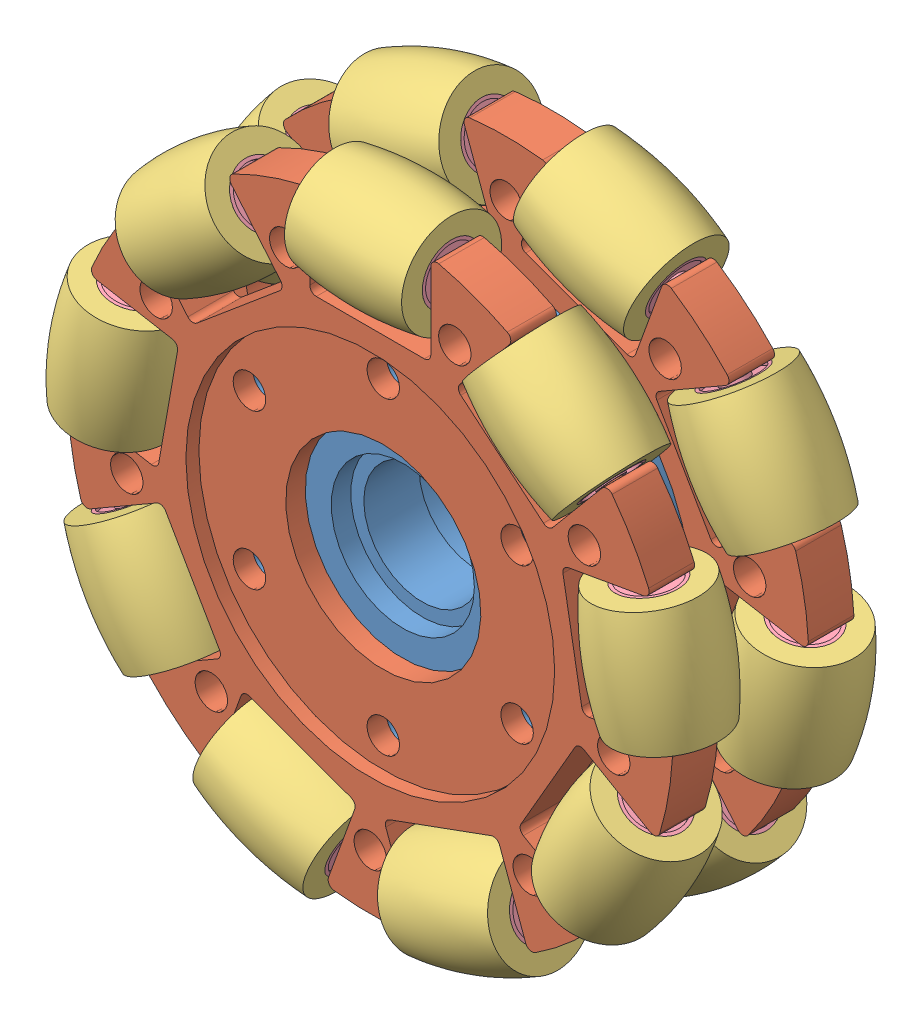
SolidWorks assembly 100mm Omni Wheel, configuration Default. Lengths in mm.
Overall size (131.92 131.45 55.1).
60 component instances, 5 part files, 8 mates.
Components (placement in the parent):
- Core-1: Core [Default] at origin size (56 56 18)
- Single Side-2: Single Side [Default] at (0 0 10.5) x (-0.5 0.866025 0) z (0 0 1) size (107.72 106.08 23.21)
  - Frame-1: Frame [Default] at origin size (92.88 91.83 7)
  - Roller_New-1: Roller_New [預設] at (0 41.5 0) x (1 0 0) z (0 -0.498092 0.867124) size (18 17 17)
  - MR93zz_3x9x4mm-1: MR93zz_3x9x4mm [預設] at (7 41.5 0) x (0 0 -1) z (1 0 0) size (9 9 4)
  - MR93zz_3x9x4mm-2: MR93zz_3x9x4mm [預設] at (-7 41.5 0) x (0 0 1) z (-1 0 0) size (9 9 4)
  - Roller_New-2: Roller_New [預設] at (-26.6757 31.7908 0) x (0.766044 0.642788 0) z (0.320168 -0.381561 0.867124) size (18 17 17)
  - Roller_New-3: Roller_New [預設] at (-40.8695 7.2064 0) x (0.173648 0.984808 0) z (0.490525 -0.086493 0.867124) size (18 17 17)
  - Roller_New-4: Roller_New [預設] at (-35.9401 -20.75 0) x (-0.5 0.866025 0) z (0.431361 0.249046 0.867124) size (18 17 17)
  - Roller_New-5: Roller_New [預設] at (-14.1938 -38.9972 0) x (-0.939693 0.34202 0) z (0.170358 0.468054 0.867124) size (18 17 17)
  - Roller_New-6: Roller_New [預設] at (14.1938 -38.9972 0) x (-0.939693 -0.34202 0) z (-0.170358 0.468054 0.867124) size (18 17 17)
  - Roller_New-7: Roller_New [預設] at (35.9401 -20.75 0) x (-0.5 -0.866025 0) z (-0.431361 0.249046 0.867124) size (18 17 17)
  - Roller_New-8: Roller_New [預設] at (40.8695 7.2064 0) x (0.173648 -0.984808 0) z (-0.490525 -0.086493 0.867124) size (18 17 17)
  - Roller_New-9: Roller_New [預設] at (26.6757 31.7908 0) x (0.766044 -0.642788 0) z (-0.320168 -0.381561 0.867124) size (18 17 17)
  - MR93zz_3x9x4mm-3: MR93zz_3x9x4mm [預設] at (-32.038 27.2913 0) x (0 0 1) z (-0.766044 -0.642788 0) size (9 9 4)
  - MR93zz_3x9x4mm-4: MR93zz_3x9x4mm [預設] at (-42.0851 0.3127 0) x (0 0 1) z (-0.173648 -0.984808 0) size (9 9 4)
  - MR93zz_3x9x4mm-5: MR93zz_3x9x4mm [預設] at (-32.4401 -26.8122 0) x (0 0 1) z (0.5 -0.866025 0) size (9 9 4)
  - MR93zz_3x9x4mm-6: MR93zz_3x9x4mm [預設] at (-7.616 -41.3914 0) x (0 0 1) z (0.939693 -0.34202 0) size (9 9 4)
  - MR93zz_3x9x4mm-7: MR93zz_3x9x4mm [預設] at (20.7717 -36.6031 0) x (0 0 1) z (0.939693 0.34202 0) size (9 9 4)
  - MR93zz_3x9x4mm-8: MR93zz_3x9x4mm [預設] at (39.4401 -14.6878 0) x (0 0 1) z (0.5 0.866025 0) size (9 9 4)
  - MR93zz_3x9x4mm-9: MR93zz_3x9x4mm [預設] at (39.654 14.1001 0) x (0 0 1) z (-0.173648 0.984808 0) size (9 9 4)
  - MR93zz_3x9x4mm-10: MR93zz_3x9x4mm [預設] at (21.3134 36.2904 0) x (0 0 1) z (-0.766044 0.642788 0) size (9 9 4)
  - MR93zz_3x9x4mm-11: MR93zz_3x9x4mm [預設] at (-21.3134 36.2904 0) x (0 0 -1) z (0.766044 0.642788 0) size (9 9 4)
  - MR93zz_3x9x4mm-12: MR93zz_3x9x4mm [預設] at (-39.654 14.1001 0) x (0 0 -1) z (0.173648 0.984808 0) size (9 9 4)
  - MR93zz_3x9x4mm-13: MR93zz_3x9x4mm [預設] at (-39.4401 -14.6878 0) x (0 0 -1) z (-0.5 0.866025 0) size (9 9 4)
  - MR93zz_3x9x4mm-14: MR93zz_3x9x4mm [預設] at (-20.7717 -36.6031 0) x (0 0 -1) z (-0.939693 0.34202 0) size (9 9 4)
  - MR93zz_3x9x4mm-15: MR93zz_3x9x4mm [預設] at (7.616 -41.3914 0) x (0 0 -1) z (-0.939693 -0.34202 0) size (9 9 4)
  - MR93zz_3x9x4mm-16: MR93zz_3x9x4mm [預設] at (32.4401 -26.8122 0) x (0 0 -1) z (-0.5 -0.866025 0) size (9 9 4)
  - MR93zz_3x9x4mm-17: MR93zz_3x9x4mm [預設] at (42.0851 0.3127 0) x (0 0 -1) z (0.173648 -0.984808 0) size (9 9 4)
  - MR93zz_3x9x4mm-18: MR93zz_3x9x4mm [預設] at (32.038 27.2913 0) x (0 0 -1) z (0.766044 -0.642788 0) size (9 9 4)
- 8mm Hub-1: 8mm Hub [預設] at (-0.1077 -0.0622 -12) x (0.5 -0.866025 0) z (0 0 -1) size (56.7 56.7 26)
- Single Side-3: Single Side [Default] at (-0.1077 -0.0622 -10.5) x (0.5 -0.866025 0) z (0 0 1) size (107.72 106.08 23.21)
  - Frame-1: Frame [Default] at origin size (92.88 91.83 7)
  - Roller_New-1: Roller_New [預設] at (0 41.5 0) x (1 0 0) z (0 -0.498092 0.867124) size (18 17 17)
  - MR93zz_3x9x4mm-1: MR93zz_3x9x4mm [預設] at (7 41.5 0) x (0 0 -1) z (1 0 0) size (9 9 4)
  - MR93zz_3x9x4mm-2: MR93zz_3x9x4mm [預設] at (-7 41.5 0) x (0 0 1) z (-1 0 0) size (9 9 4)
  - Roller_New-2: Roller_New [預設] at (-26.6757 31.7908 0) x (0.766044 0.642788 0) z (0.320168 -0.381561 0.867124) size (18 17 17)
  - Roller_New-3: Roller_New [預設] at (-40.8695 7.2064 0) x (0.173648 0.984808 0) z (0.490525 -0.086493 0.867124) size (18 17 17)
  - Roller_New-4: Roller_New [預設] at (-35.9401 -20.75 0) x (-0.5 0.866025 0) z (0.431361 0.249046 0.867124) size (18 17 17)
  - Roller_New-5: Roller_New [預設] at (-14.1938 -38.9972 0) x (-0.939693 0.34202 0) z (0.170358 0.468054 0.867124) size (18 17 17)
  - Roller_New-6: Roller_New [預設] at (14.1938 -38.9972 0) x (-0.939693 -0.34202 0) z (-0.170358 0.468054 0.867124) size (18 17 17)
  - Roller_New-7: Roller_New [預設] at (35.9401 -20.75 0) x (-0.5 -0.866025 0) z (-0.431361 0.249046 0.867124) size (18 17 17)
  - Roller_New-8: Roller_New [預設] at (40.8695 7.2064 0) x (0.173648 -0.984808 0) z (-0.490525 -0.086493 0.867124) size (18 17 17)
  - Roller_New-9: Roller_New [預設] at (26.6757 31.7908 0) x (0.766044 -0.642788 0) z (-0.320168 -0.381561 0.867124) size (18 17 17)
  - MR93zz_3x9x4mm-3: MR93zz_3x9x4mm [預設] at (-32.038 27.2913 0) x (0 0 1) z (-0.766044 -0.642788 0) size (9 9 4)
  - MR93zz_3x9x4mm-4: MR93zz_3x9x4mm [預設] at (-42.0851 0.3127 0) x (0 0 1) z (-0.173648 -0.984808 0) size (9 9 4)
  - MR93zz_3x9x4mm-5: MR93zz_3x9x4mm [預設] at (-32.4401 -26.8122 0) x (0 0 1) z (0.5 -0.866025 0) size (9 9 4)
  - MR93zz_3x9x4mm-6: MR93zz_3x9x4mm [預設] at (-7.616 -41.3914 0) x (0 0 1) z (0.939693 -0.34202 0) size (9 9 4)
  - MR93zz_3x9x4mm-7: MR93zz_3x9x4mm [預設] at (20.7717 -36.6031 0) x (0 0 1) z (0.939693 0.34202 0) size (9 9 4)
  - MR93zz_3x9x4mm-8: MR93zz_3x9x4mm [預設] at (39.4401 -14.6878 0) x (0 0 1) z (0.5 0.866025 0) size (9 9 4)
  - MR93zz_3x9x4mm-9: MR93zz_3x9x4mm [預設] at (39.654 14.1001 0) x (0 0 1) z (-0.173648 0.984808 0) size (9 9 4)
  - MR93zz_3x9x4mm-10: MR93zz_3x9x4mm [預設] at (21.3134 36.2904 0) x (0 0 1) z (-0.766044 0.642788 0) size (9 9 4)
  - MR93zz_3x9x4mm-11: MR93zz_3x9x4mm [預設] at (-21.3134 36.2904 0) x (0 0 -1) z (0.766044 0.642788 0) size (9 9 4)
  - MR93zz_3x9x4mm-12: MR93zz_3x9x4mm [預設] at (-39.654 14.1001 0) x (0 0 -1) z (0.173648 0.984808 0) size (9 9 4)
  - MR93zz_3x9x4mm-13: MR93zz_3x9x4mm [預設] at (-39.4401 -14.6878 0) x (0 0 -1) z (-0.5 0.866025 0) size (9 9 4)
  - MR93zz_3x9x4mm-14: MR93zz_3x9x4mm [預設] at (-20.7717 -36.6031 0) x (0 0 -1) z (-0.939693 0.34202 0) size (9 9 4)
  - MR93zz_3x9x4mm-15: MR93zz_3x9x4mm [預設] at (7.616 -41.3914 0) x (0 0 -1) z (-0.939693 -0.34202 0) size (9 9 4)
  - MR93zz_3x9x4mm-16: MR93zz_3x9x4mm [預設] at (32.4401 -26.8122 0) x (0 0 -1) z (-0.5 -0.866025 0) size (9 9 4)
  - MR93zz_3x9x4mm-17: MR93zz_3x9x4mm [預設] at (42.0851 0.3127 0) x (0 0 -1) z (0.173648 -0.984808 0) size (9 9 4)
  - MR93zz_3x9x4mm-18: MR93zz_3x9x4mm [預設] at (32.038 27.2913 0) x (0 0 -1) z (0.766044 -0.642788 0) size (9 9 4)
Mates (geometry in assembly coordinates):
- 重合/共線/共點213: coordinate: point of Core-1; point of assembly
- 重合/共線/共點215: coincident: circle of Core-1; circle of Single Side-2/Frame-1
- 重合/共線/共點216: coincident: circle of Core-1; circle of Single Side-2/Frame-1
- 同軸心1: concentric: circle of 8mm Hub-1; circle of Single Side-3/Frame-1
- 同軸心2: concentric: circle of 8mm Hub-1; circle of Single Side-3/Frame-1
- 重合/共線/共點217: coincident: plane of 8mm Hub-1 through (-0.1077 -0.0622 -12) normal (0 0 1); plane of Single Side-3/Frame-1 through (-0.1077 -0.0622 -12) normal (0 0 -1)
- 重合/共線/共點218: coincident: plane of Single Side-2/Frame-1 through (0 0 12) normal (0 0 1); plane of ? through (0 0 12) normal (0 0 -1)
- 同軸心6: concentric: cylinder of Single Side-2/Frame-1 through (20.5681 11.875 7) axis (0 0 1) radius 2.5; cylinder of ? through (20.5681 11.875 12) axis (0 0 1) radius 2.5
